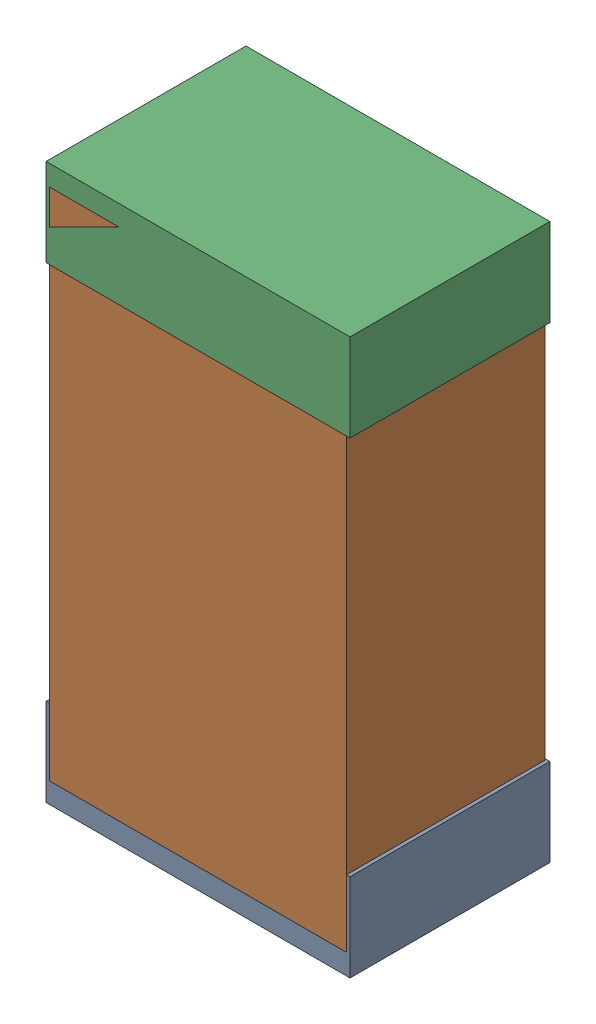
SolidWorks assembly R11Kanaloa_v2.0.0_Motor, configuration Default. Lengths in mm.
Overall size (1.3 2.38 0.85).
6 component instances, 2 part files, 0 mates.
Components (placement in the parent):
- 330415056-1: 330415056 [Default] at (43.688 65.294 -1.9574) size (1.3 0.38 0.85)
  - Extruded_2-1: Extruded_2 [Default] at origin size (1.3 0.38 0.85)
- 334787376-1: 334787376 [Default] at (43.688 66.294 -1.9524) size (1.27 2.2 0.85)
  - Extruded_16-1: Extruded_16 [Default] at origin size (1.27 2.2 0.85)
- 330415056-2: 330415056 [Default] at (43.688 67.294 -1.9574) size (1.3 0.38 0.85)
  - Extruded_2-1: Extruded_2 [Default] at origin size (1.3 0.38 0.85)
